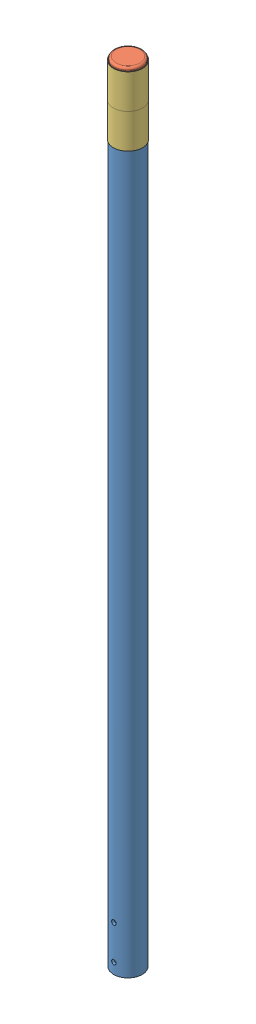
SolidWorks assembly TE-23037, configuration Default. Lengths in mm.
Overall size (43.18 1165.22 43.18).
4 component instances, 3 part files, 6 mates.
Components (placement in the parent):
- TE-23017-1: TE-23017 [Default] at (573.0154 190.2203 1099.1574) size (42.16 1160.46 42.16)
- CCF-RT-13-1-1: CCF-RT-13-1 [Default] at (573.0154 1337.9828 1099.1574) size (41.27 17.46 41.27)
- tape_VISIONTARGET-1: tape_VISIONTARGET [Default] at (573.0154 1299.8828 1099.1574) size (43.18 50.8 43.18)
- tape_VISIONTARGET-2: tape_VISIONTARGET [Default] at (573.0154 1249.0828 1099.1574) size (43.18 50.8 43.18)
Mates (geometry in assembly coordinates):
- Coincident1: coincident anti-aligned: plane of TE-23036-1 through (573.0154 1350.6828 1099.1574) normal (0 1 0); plane of CCF-RT-13-1-1 through (588.8904 1350.6828 1099.1574) normal (0 -1 0)
- Concentric1: concentric aligned: cylinder of TE-23036-1 through (573.0154 1350.6828 1099.1574) axis (0 -1 0) radius 21.082; cylinder of CCF-RT-13-1-1 through (573.0154 1337.9828 1099.1574) axis (0 -1 0) radius 20.6375
- Concentric2: concentric aligned: cylinder of TE-23036-1 through (573.0154 1350.6828 1099.1574) axis (0 -1 0) radius 21.082; cylinder of tape_VISIONTARGET-1 through (573.0154 1350.6828 1099.1574) axis (0 -1 0) radius 21.59
- Concentric3: concentric aligned: cylinder of TE-23036-1 through (573.0154 1350.6828 1099.1574) axis (0 -1 0) radius 21.082; cylinder of tape_VISIONTARGET-2 through (573.0154 1299.8828 1099.1574) axis (0 -1 0) radius 21.59
- Coincident2: coincident aligned: plane of TE-23036-1 through (573.0154 1350.6828 1099.1574) normal (0 1 0); plane of tape_VISIONTARGET-1 through (573.0154 1350.6828 1099.1574) normal (0 1 0)
- Coincident3: coincident anti-aligned: plane of tape_VISIONTARGET-1 through (573.0154 1299.8828 1099.1574) normal (0 -1 0); plane of tape_VISIONTARGET-2 through (573.0154 1299.8828 1099.1574) normal (0 1 0)
